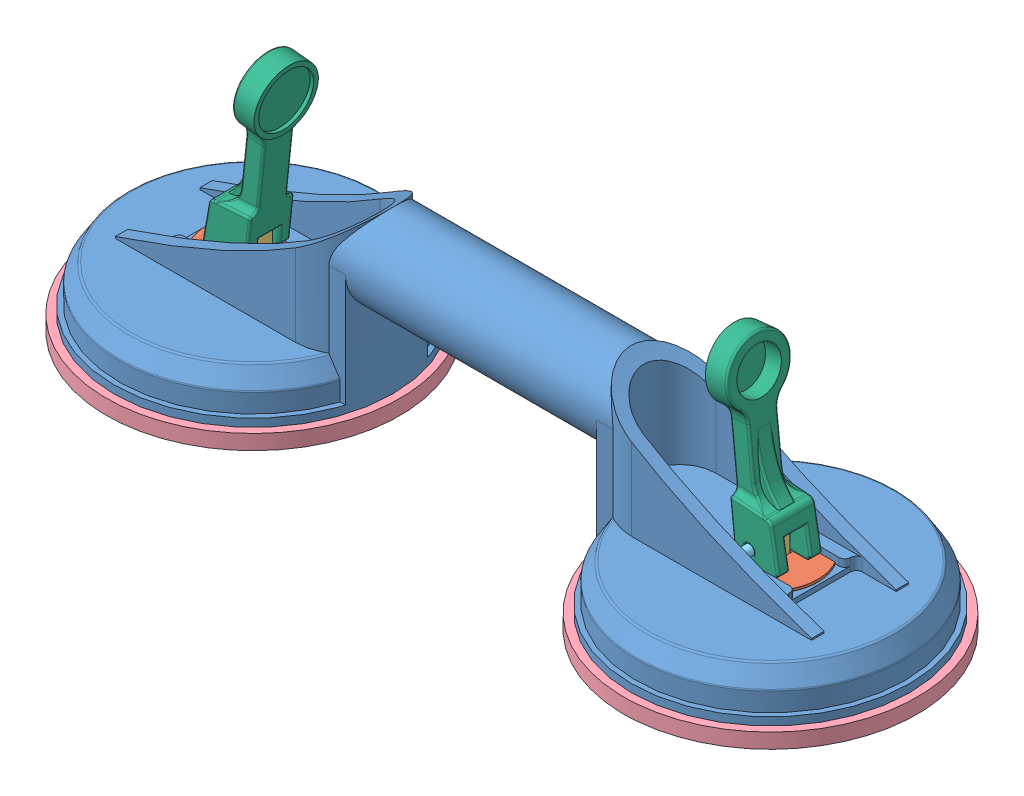
SolidWorks assembly 4000-817214_2-Cup Suction Lifter, configuration Standard. Lengths in mm.
Overall size (329.25 103.81 121.25).
11 component instances, 6 part files, 12 mates.
Components (placement in the parent):
- 4000-817214_Body-1: 4000-817214_Body [Standard] at origin size (320 66.8 112)
- 4000-817214_Washer-1: 4000-817214_Washer [Standard] at (208 20 0) size (28.5 1 19)
- 4000-817214_Shaft-1: 4000-817214_Shaft [Standard] at (208 0 0) size (8 31 8)
- 4000-817214_Cup-1: 4000-817214_Cup [Standard] at (208 -6 0) x (0.999609 0 -0.027958) z (0.027958 0 0.999609) size (118 8 118)
- 4000-817214_Splint-1: 4000-817214_Splint [Standard] at (208 26 -12.5) size (4 4 25)
- 4000-817214_Washer-2: 4000-817214_Washer [Standard] at (0 20 0) x (-1 0 0) z (0 0 -1) size (28.5 1 19)
- 4000-817214_Shaft-2: 4000-817214_Shaft [Standard] x (-1 0 0) z (0 0 -1) size (8 31 8)
- 4000-817214_Cup-2: 4000-817214_Cup [Standard] at (0 -6 0) x (-0.999609 0 -0.027958) z (0.027958 0 -0.999609) size (118 8 118)
- 4000-817214_Splint-2: 4000-817214_Splint [Standard] at (0 26 12.5) x (-1 0 0) z (0 0 -1) size (4 4 25)
- 4000-817214_Lever-1: 4000-817214_Lever [Standard] at (196.1712 81.1426 0) x (-0.104528 0.994522 0) z (0 0 -1) size (75 18.96 25.8)
- 4000-817214_Lever-2: 4000-817214_Lever [Standard] at (11.8288 81.1426 0) x (0.104528 0.994522 0) z (0 0 1) size (75 18.96 25.8)
Mates (geometry in assembly coordinates):
- Deckungsgleich1: coincident anti-aligned: plane of 4000-817214_Body-1 through (208 20 0) normal (0 1 0); plane of 4000-817214_Washer-1 through (208 20 0) normal (0 -1 0)
- Konzentrisch1: concentric anti-aligned: circle of 4000-817214_Body-1; circle of 4000-817214_Washer-1
- Breite1: width anti-aligned: plane of 4000-817214_Washer-1 through (203.75 21 0) normal (1 0 0); plane of 4000-817214_Washer-1 through (212.25 21 0) normal (-1 0 0); plane of 4000-817214_Shaft-1 through (204 31 -4) normal (-1 0 0); plane of 4000-817214_Shaft-1 through (212 31 -4) normal (1 0 0)
- Breite2: width anti-aligned: plane of 4000-817214_Washer-1 through (208 21 4.25) normal (0 0 -1); plane of 4000-817214_Washer-1 through (208 21 -4.25) normal (0 0 1); plane of 4000-817214_Shaft-1 through (204 31 4) normal (0 0 1); plane of 4000-817214_Shaft-1 through (204 31 -4) normal (0 0 -1)
- Deckungsgleich3: coincident anti-aligned: plane of 4000-817214_Shaft-1 through (208 0 0) normal (0 -1 0); plane of 4000-817214_Cup-1 through (208 0 0) normal (0 1 0)
- Konzentrisch2: concentric aligned: cylinder of 4000-817214_Body-1 through (208 65 0) axis (0 -1 0) radius 56; cylinder of 4000-817214_Cup-1 through (208 0 0) axis (0 -1 0) radius 59
- Deckungsgleich4: coincident anti-aligned: plane of 4000-817214_Body-1 through (208 0 0) normal (0 -1 0); plane of 4000-817214_Cup-1 through (208 0 0) normal (0 1 0)
- Konzentrisch3: concentric anti-aligned: cylinder of 4000-817214_Shaft-1 through (208 26 -4) axis (0 0 1) radius 2; cylinder of 4000-817214_Splint-1 through (208 26 12.5) axis (0 0 -1) radius 2
- Breite3: width anti-aligned: plane of 4000-817214_Splint-1 through (208 26 12.5) normal (0 0 1); plane of 4000-817214_Splint-1 through (208 26 -12.5) normal (0 0 -1); plane of 4000-817214_Shaft-1 through (204 31 -4) normal (0 0 -1); plane of 4000-817214_Shaft-1 through (204 31 4) normal (0 0 1)
- Breite4: width anti-aligned: plane of 4000-817214_Lever-1 through (196.1712 81.1426 -4.3) normal (0 0 1); plane of 4000-817214_Lever-1 through (196.1712 81.1426 4.3) normal (0 0 -1); plane of 4000-817214_Shaft-1 through (204 31 -4) normal (0 0 -1); plane of 4000-817214_Shaft-1 through (204 31 4) normal (0 0 1)
- Konzentrisch4: concentric aligned: cylinder of 4000-817214_Splint-1 through (208 26 12.5) axis (0 0 -1) radius 2; cylinder of 4000-817214_Lever-1 through (208 26 8.85) axis (0 0 -1) radius 2
- Parallel1: parallel anti-aligned: plane of 4000-817214_Washer-1 through (208 21 0) normal (0 1 0); plane of 4000-817214_Lever-1 through (196.1712 21 8.85) normal (0 -1 0)
